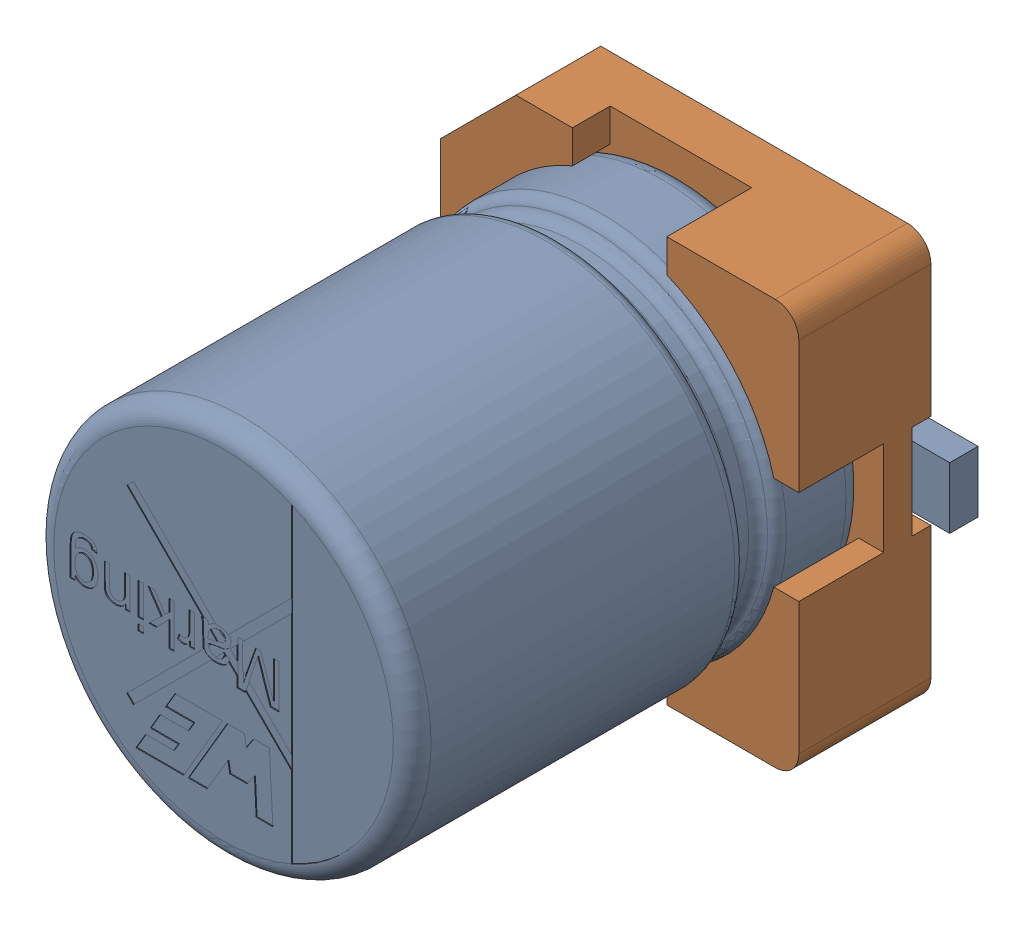
SolidWorks assembly C12, configuration Default. Lengths in mm.
Overall size (5 4.3 5.5).
3 component instances, 2 part files, 0 mates.
Components (placement in the parent):
- 4x5.5x1-1: 4x5.5x1 [Default] at (46.4567 24.4348 0.1) x (0 -1 0) z (0 0 1) size (4.3 5 5.5)
  - capicitor_4x5.5x1-1: capicitor_4x5.5x1 [Default] at (0 0 0.5) x (0 -1 0) z (0 0 1) size (5 4 5.5)
  - Base___X2__03A6__X0__4Capacitor-1: Base___X2__03A6__X0__4Capacitor [Default] at origin size (4.3 4.3 1.46)
